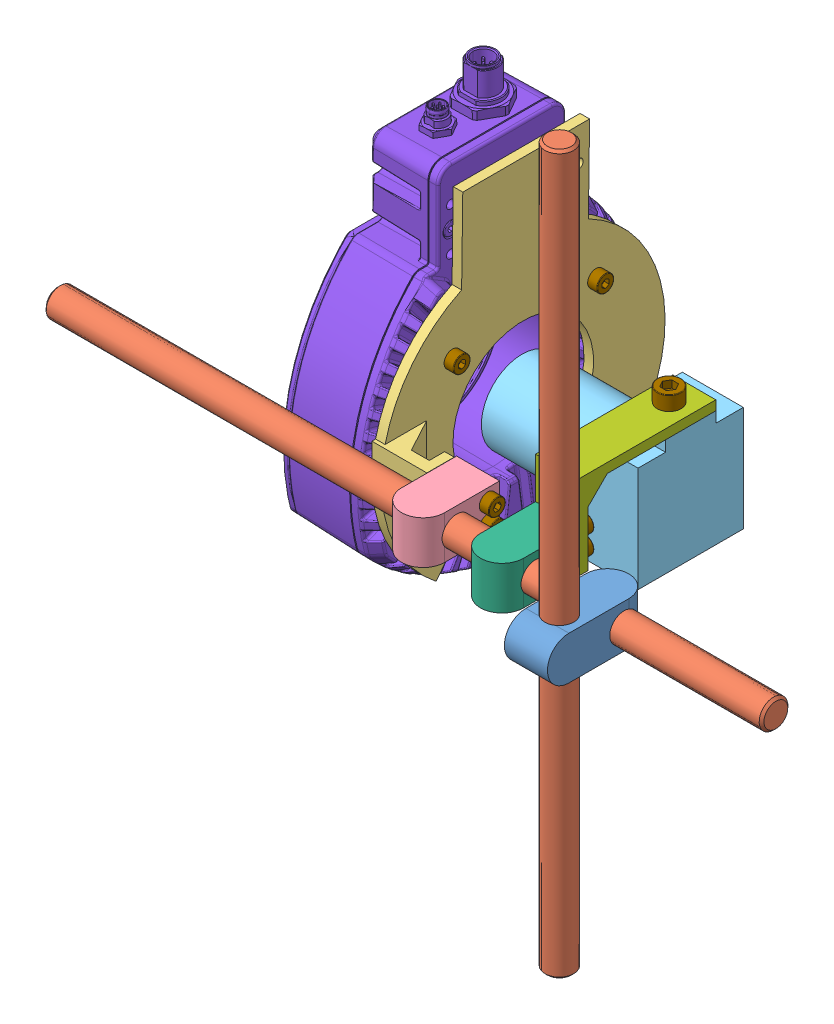
SolidWorks assembly Cam_ilum, configuration Default. Lengths in mm.
Overall size (300 300 160.71).
20 component instances, 9 part files, 41 mates.
Components (placement in the parent):
- ALK-1: ALK [Default] at (17.1563 17.329 35.895) size (18 18 43)
- veio-1: veio [Default] at (-210.3955 25.935 20.8493) x (1 0 0) z (0 0.995793 0.091628) size (300 12 12)
- veio-2: veio [Default] at (17.1563 207.0581 38.895) x (0 -1 0) z (-0.68605 0 -0.727555) size (300 12 12)
- suporte led-1: suporte led [Default] at (-84.8439 21.6156 -44.0107) x (0 0.013819 0.999905) z (0 0.999905 -0.013819) size (118.74 23 136.22)
- amwn-1: amwn [Default] at (-52.8439 16.935 14.3493) x (0 1 0) z (1 0 0) size (18 32 18)
- Camara2-2: Camara2 [Default] at (-36.3609 48.1156 -66.0107) x (0 0 1) z (0 1 0) size (44 70.5 48.5)
- aqcm12-2: aqcm12 [Default] at (-20.8609 16.935 8.7094) x (0 1 0) z (1 0 0) size (18 32 18)
- Suporte_cam_ids-1: Suporte_cam_ids [Default] at (-28.8609 48.1156 -54.5107) x (0 0 1) z (0 1 0) size (57.36 18 35.18)
- effi-ring.step-1: effi-ring.step [Default] at (-93.8439 21.1461 -44.3704) x (0 0 -1) z (0 1 0) size (126.88 79.94 182.14)
- CHC-1: CHC [Vis CHC M6x10] at (-19.8609 52.1156 -44.0107) size (10 16 10)
- CHC-2: CHC [Vis CHC M4x8] at (-80.8439 51.1981 -74.4224) x (0 -1 0) z (0 0 1) size (7 12 7)
- CHC-3: CHC [Vis CHC M4x8] at (-80.8439 -8.7961 -73.5933) x (0 -1 0) z (0 0 1) size (7 12 7)
- CHC-4: CHC [Vis CHC M4x8] at (-80.8439 52.0273 -14.4282) x (0 -1 0) z (0 0 1) size (7 12 7)
- CHC-5: CHC [Vis CHC M4x8] at (-80.8439 -7.967 -13.599) x (0 0.828906 -0.559388) z (0 -0.559388 -0.828906) size (7 12 7)
- CHC-7: CHC [Vis CHC M4x8] at (-43.8439 21.935 7.8493) x (0 -1 0) z (0 0 1) size (7 12 7)
- CHC-8: CHC [Vis CHC M4x8] at (-43.8439 29.935 7.8493) x (0 0.828906 -0.559388) z (0 -0.559388 -0.828906) size (7 12 7)
- CHC-9: CHC [Vis CHC M4x8] at (-23.8609 21.9356 -1.1507) x (0 -1 0) z (1 0 0) size (7 12 7)
- CHC-10: CHC [Vis CHC M4x8] at (-15.8609 21.9356 -1.1507) x (-0.559388 0.828906 0) z (-0.828906 -0.559388 0) size (7 12 7)
- CHC-11: CHC [Vis CHC M4x8] at (-23.8609 29.9356 -1.1507) x (-0.559388 0.828906 0) z (-0.828906 -0.559388 0) size (7 12 7)
- CHC-12: CHC [Vis CHC M4x8] at (-15.8609 29.9356 -1.1507) x (-0.559388 0.828906 0) z (-0.828906 -0.559388 0) size (7 12 7)
Mates (geometry in assembly coordinates):
- Concentric1: concentric anti-aligned: cylinder of ALK-1 through (8.1563 25.935 20.8493) axis (1 0 0) radius 6; cylinder of veio-1 through (89.6045 25.935 20.8493) axis (-1 0 0) radius 6
- Concentric2: concentric anti-aligned: cylinder of ALK-1 through (17.1563 35.329 38.895) axis (0 -1 0) radius 6; cylinder of veio-2 through (17.1563 -92.9419 38.895) axis (0 1 0) radius 6
- Parallel4: parallel aligned: plane of suporte led-1 through (-80.8439 110.1779 -18.7322) normal (0 1 0); plane of amwn-1 through (-52.8439 34.935 25.8493) normal (0 1 0)
- Coincident14: coincident anti-aligned: plane of suporte led-1 through (-61.8439 17.0379 15.2693) normal (1 0 0); plane of amwn-1 through (-61.8439 34.935 2.8493) normal (-1 0 0)
- Concentric15: concentric anti-aligned: cylinder of veio-1 through (89.6045 25.935 20.8493) axis (-1 0 0) radius 6; cylinder of amwn-1 through (-61.8439 25.935 20.8493) axis (1 0 0) radius 6
- Concentric16: concentric aligned: cylinder of suporte led-1 through (-61.8439 21.935 7.8493) axis (1 0 0) radius 2; cylinder of amwn-1 through (-43.8439 21.935 7.8493) axis (1 0 0) radius 1.65
- Parallel10: parallel aligned: plane of amwn-1 through (-52.8439 34.935 25.8493) normal (0 1 0)
- Concentric20: concentric anti-aligned: cylinder of suporte led-1 through (-80.8439 21.6156 -44.0107) axis (-1 0 0) radius 29.4; cylinder of Camara2-2 through (-81.3609 21.6156 -44.0107) axis (1 0 0) radius 17
- Concentric21: concentric anti-aligned: cylinder of veio-1 through (89.6045 25.935 20.8493) axis (-1 0 0) radius 6; cylinder of aqcm12-2 through (-28.8609 25.935 20.8493) axis (1 0 0) radius 6
- Parallel11: parallel anti-aligned: plane of aqcm12-2 through (-10.8609 34.935 2.8493) normal (0 0 -1)
- Parallel12: parallel aligned: plane of amwn-1 through (-43.8439 34.935 2.8493) normal (0 0 -1); plane of aqcm12-2 through (-10.8609 34.935 2.8493) normal (0 0 -1)
- Parallel13: parallel anti-aligned: plane of Camara2-2 through (-10.8609 48.1156 -22.0107) normal (0 0 1); plane of aqcm12-2 through (-10.8609 34.935 2.8493) normal (0 0 -1)
- Coincident26: coincident aligned: plane of Camara2-2 through (-10.8609 48.1156 -66.0107) normal (1 0 0); plane of aqcm12-2 through (-10.8609 34.935 25.8493) normal (1 0 0)
- Coincident27: coincident aligned: plane of Camara2-2 through (-10.8609 48.1156 -66.0107) normal (1 0 0); plane of Suporte_cam_ids-1 through (-10.8609 52.1156 -54.5107) normal (1 0 0)
- Coincident28: coincident anti-aligned: plane of aqcm12-2 through (-10.8609 34.935 2.8493) normal (0 0 -1); plane of Suporte_cam_ids-1 through (-28.8609 52.1156 2.8493) normal (0 0 1)
- Coincident29: coincident anti-aligned: plane of Camara2-2 through (-10.8609 48.1156 -66.0107) normal (0 1 0); plane of Suporte_cam_ids-1 through (-28.8609 48.1156 -54.5107) normal (0 -1 0)
- Concentric22: concentric aligned: cylinder of suporte led-1 through (-80.8439 51.1981 -74.4224) axis (1 0 0) radius 2; cylinder of effi-ring.step-1 through (-84.8439 51.1981 -74.4224) axis (1 0 0) radius 1.65
- Parallel14: parallel aligned: cylinder of suporte led-1 through (-80.8439 -8.7961 -73.5933) axis (1 0 0) radius 2; cylinder of effi-ring.step-1 through (-84.8439 -8.9059 -74.4224) axis (1 0 0) radius 1.65
- Coincident30: coincident anti-aligned: plane of suporte led-1 through (-84.8439 21.6156 -44.0107) normal (-1 0 0); plane of effi-ring.step-1 through (-84.8439 21.1461 -44.3704) normal (1 0 0)
- Concentric25: concentric aligned: cylinder of Suporte_cam_ids-1 through (-19.8609 48.1156 -44.0107) axis (0 1 0) radius 3.3; cylinder of CHC-1 through (-19.8609 42.1156 -44.0107) axis (0 1 0) radius 3
- Coincident31: coincident anti-aligned: plane of Suporte_cam_ids-1 through (-28.8609 52.1156 -54.5107) normal (0 1 0); plane of CHC-1 through (-19.8609 52.1156 -44.0107) normal (0 -1 0)
- Coincident32: coincident anti-aligned: plane of suporte led-1 through (-80.8439 21.6156 -44.0107) normal (1 0 0); plane of CHC-2 through (-80.8439 51.1981 -74.4224) normal (-1 0 0)
- Concentric27: concentric aligned: cylinder of suporte led-1 through (-80.8439 51.1981 -74.4224) axis (1 0 0) radius 2; cylinder of CHC-2 through (-88.8439 51.1981 -74.4224) axis (1 0 0) radius 2
- Coincident33: coincident anti-aligned: plane of suporte led-1 through (-80.8439 21.6156 -44.0107) normal (1 0 0); plane of CHC-3 through (-80.8439 -8.7961 -73.5933) normal (-1 0 0)
- Concentric28: concentric anti-aligned: cylinder of suporte led-1 through (-80.8439 -8.7961 -73.5933) axis (1 0 0) radius 2; cylinder of CHC-3 through (-76.8439 -8.7961 -73.5933) axis (-1 0 0) radius 3.5
- Concentric29: concentric aligned: cylinder of suporte led-1 through (-80.8439 52.0273 -14.4282) axis (1 0 0) radius 2; cylinder of CHC-4 through (-88.8439 52.0273 -14.4282) axis (1 0 0) radius 2
- Coincident34: coincident aligned: plane of suporte led-1 through (-80.8439 21.6156 -44.0107) normal (1 0 0); circle of CHC-4
- Concentric30: concentric aligned: cylinder of suporte led-1 through (-80.8439 -7.967 -13.599) axis (1 0 0) radius 2; cylinder of CHC-5 through (-88.8439 -7.967 -13.599) axis (1 0 0) radius 2
- Coincident35: coincident aligned: plane of suporte led-1 through (-80.8439 21.6156 -44.0107) normal (1 0 0); circle of CHC-5
- Coincident36: coincident anti-aligned: plane of amwn-1 through (-43.8439 34.935 2.8493) normal (1 0 0); plane of CHC-7 through (-43.8439 21.935 7.8493) normal (-1 0 0)
- Concentric32: concentric aligned: cylinder of amwn-1 through (-43.8439 21.935 7.8493) axis (1 0 0) radius 1.65; cylinder of CHC-7 through (-51.8439 21.935 7.8493) axis (1 0 0) radius 2
- Coincident38: coincident anti-aligned: plane of amwn-1 through (-43.8439 34.935 2.8493) normal (1 0 0); plane of CHC-8 through (-43.8439 29.935 7.8493) normal (-1 0 0)
- Concentric33: concentric anti-aligned: circle of amwn-1; cylinder of CHC-8 through (-39.8439 29.935 7.8493) axis (-1 0 0) radius 3.5
- Coincident39: coincident anti-aligned: plane of Suporte_cam_ids-1 through (-28.8609 48.1156 -1.1507) normal (0 0 -1); plane of CHC-9 through (-23.8609 21.9356 -1.1507) normal (0 0 1)
- Concentric34: concentric aligned: cylinder of Suporte_cam_ids-1 through (-23.8609 21.9356 -1.1507) axis (0 0 1) radius 2.2; cylinder of CHC-9 through (-23.8609 21.9356 -5.1507) axis (0 0 1) radius 3.5
- Coincident40: coincident anti-aligned: plane of Suporte_cam_ids-1 through (-28.8609 48.1156 -1.1507) normal (0 0 -1); plane of CHC-10 through (-15.8609 21.9356 -1.1507) normal (0 0 1)
- Concentric35: concentric aligned: cylinder of Suporte_cam_ids-1 through (-15.8609 21.9356 -1.1507) axis (0 0 1) radius 2.2; cylinder of CHC-10 through (-15.8609 21.9356 -5.1507) axis (0 0 1) radius 3.5
- Coincident41: coincident anti-aligned: plane of Suporte_cam_ids-1 through (-28.8609 48.1156 -1.1507) normal (0 0 -1); plane of CHC-11 through (-23.8609 29.9356 -1.1507) normal (0 0 1)
- Concentric36: concentric aligned: cylinder of Suporte_cam_ids-1 through (-23.8609 29.9356 -1.1507) axis (0 0 1) radius 2.2; cylinder of CHC-11 through (-23.8609 29.9356 -5.1507) axis (0 0 1) radius 3.5
- Coincident42: coincident anti-aligned: plane of Suporte_cam_ids-1 through (-28.8609 48.1156 -1.1507) normal (0 0 -1); plane of CHC-12 through (-15.8609 29.9356 -1.1507) normal (0 0 1)
- Concentric37: concentric aligned: cylinder of Suporte_cam_ids-1 through (-15.8609 29.9356 -1.1507) axis (0 0 1) radius 2.2; cylinder of CHC-12 through (-15.8609 29.9356 -5.1507) axis (0 0 1) radius 3.5
